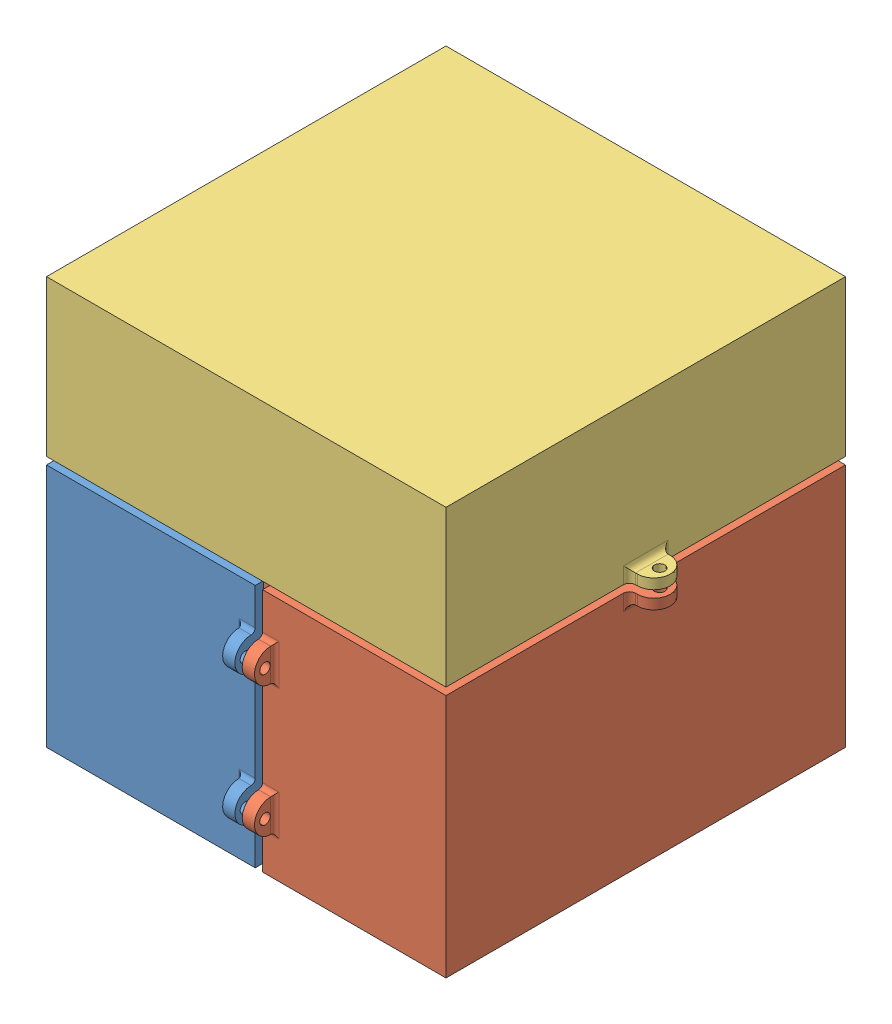
SolidWorks assembly box1, configuration Default. Lengths in mm.
Overall size (110 100 108).
3 component instances, 3 part files, 3 mates.
Components (placement in the parent):
- lx1-1: lx1 [Default] at (-112.1154 40.7854 212.7876) size (57.2 65 108)
- rx1-1: rx1 [Default] at (-65.6154 40.7854 212.7876) x (-1 0 0) z (0 0 -1) size (56 65 108)
- top1-1: top1 [Default] at (-89.6154 140.7854 212.7876) x (-1 0 0) z (0 0 1) size (110 38.2 98)
Mates (geometry in assembly coordinates):
- Coincident1: coincident anti-aligned: line of lx1-1 through (-90.6154 105.7854 257.7876) axis (0 -1 0); line of rx1-1 through (-90.6154 44.7854 257.7876) axis (0 1 0)
- Coincident2: coincident anti-aligned: line of lx1-1 through (-90.6154 105.7854 259.7876) axis (0 0 -1); line of rx1-1 through (-90.6154 105.7854 257.7876) axis (0 0 1)
- Coincident3: coincident: point of rx1-1; point of top1-1
